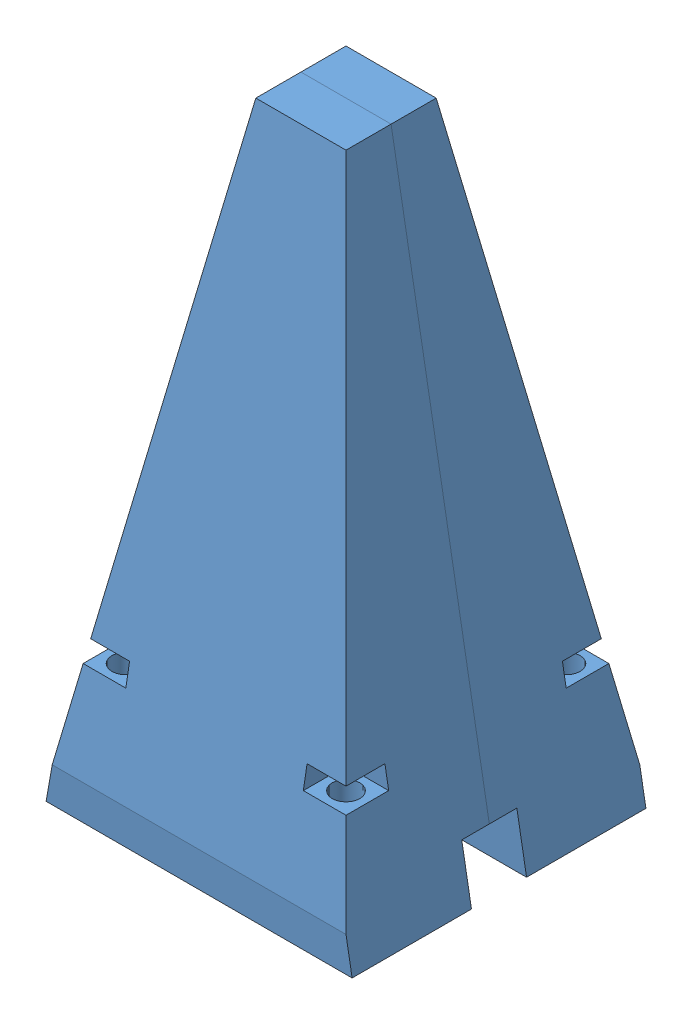
SolidWorks assembly stick_antenna_asm, configuration 預設. Lengths in mm.
Overall size (50 100 48).
3 component instances, 2 part files, 6 mates.
Components (placement in the parent):
- stick_antenna_cap-1: stick_antenna_cap [預設] at (112.0365 -132.4231 0) size (50 100 24)
- stick_antenna_cap-2: stick_antenna_cap [預設] at (112.0365 -132.4231 0) x (-1 0 0) z (0 0 -1) size (50 100 24)
- stick_antenna_434MHz-1: stick_antenna_434MHz [預設] at (112.0365 -114.4231 0) x (0 1 0) z (-0.546944 0 0.837169) size (76.2 12.8 12.8)
Mates (geometry in assembly coordinates):
- 重合/共線/共點1: coincident: plane of stick_antenna_cap-1 through (112.0365 -132.4231 0) normal (0 0 1); plane of stick_antenna_cap-2 through (112.0365 -132.4231 0) normal (0 0 -1)
- 重合/共線/共點2: coincident: line of stick_antenna_cap-1 through (14.7346 119.4038 -32.4231) axis (0 -1 0); line of stick_antenna_cap-2 through (104.6692 -32.4231 0) axis (1 0 0)
- 重合/共線/共點3: coincident: plane of stick_antenna_cap-1 through (87.0365 -132.4231 -25) normal (-0.984808 0.173648 0); plane of stick_antenna_cap-2 through (87.0365 -132.4231 25) normal (-0.984808 0.173648 0)
- 重合/共線/共點4: coincident: plane of assembly; plane of stick_antenna_cap-1 through (112.0365 -132.4231 0) normal (0 0 1); plane of assembly
- 重合/共線/共點5: coincident: plane of stick_antenna_cap-2 through (118.4365 -114.4231 0) normal (0 1 0); circle of stick_antenna_434MHz-1
- 同軸心1: concentric: cylinder of stick_antenna_cap-2 through (112.0365 -105.8231 0) axis (0 1 0) radius 6.4; cylinder of stick_antenna_434MHz-1 through (112.0365 -105.8231 0) axis (0 1 0) radius 6.4
